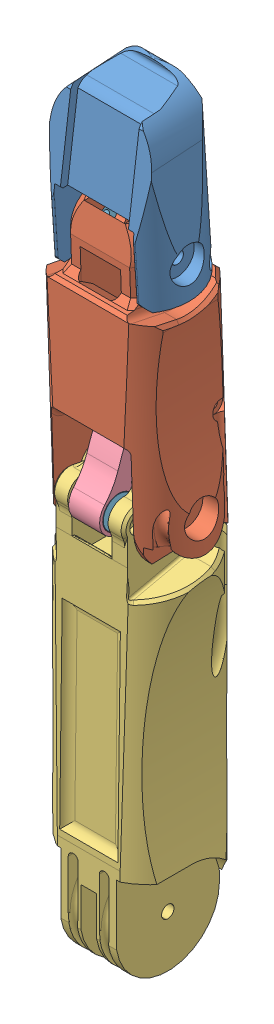
SolidWorks assembly assembly middle finger, configuration Default. Lengths in mm.
Overall size (26.12 124.19 19.82).
12 component instances, 5 part files, 24 mates.
Components (placement in the parent):
- middle link1-2: middle link1 [Default] at (0 -22.0125 -35.7101) x (1 0 0) z (0 -0.067342 0.99773) size (19.5 27.22 13.31)
- middle link2-2: middle link2 [Default] at (0 -57.5994 -36.9948) x (1 0 0) z (0 -0.036077 0.999349) size (23.01 45.61 15.34)
- middle link3-1: middle link3 [Default] at (0 -115.2194 -36.9948) size (26.12 70.93 19.35)
- middle linkage-1: middle linkage [Default] at (0 -39.6096 -36.4016) x (1 0 0) z (0 0.999451 0.033137) size (5 17.7 38.56)
- bearing 1.5-4-5-2-3: bearing 1.5-4-5-2 [Default] at (4.35 -57.5994 -36.9948) x (0 -0.484483 0.8748) z (0 0.8748 0.484483) size (5 2 5)
- bearing 1.5-4-5-2-4: bearing 1.5-4-5-2 [Default] at (0.5 -57.5994 -31.1248) x (0 -0.673592 0.739103) z (0 0.739103 0.673592) size (5 2 5)
- bearing 1.5-4-5-2-5: bearing 1.5-4-5-2 [Default] at (-4.35 -57.5994 -36.9948) x (0 0.90845 0.417993) z (0 -0.417993 0.90845) size (5 2 5)
- bearing 1.5-4-5-2-6: bearing 1.5-4-5-2 [Default] at (-0.5 -57.5994 -31.1248) x (0 0.90845 0.417993) z (0 -0.417993 0.90845) size (5 2 5)
- bearing 1.5-4-5-2-9: bearing 1.5-4-5-2 [Default] at (-0.5 -24.8761 -41.5454) x (0 0.90845 0.417993) z (0 -0.417993 0.90845) size (5 2 5)
- bearing 1.5-4-5-2-10: bearing 1.5-4-5-2 [Default] at (0.5 -24.8761 -41.5454) x (0 -0.673592 0.739103) z (0 0.739103 0.673592) size (5 2 5)
- bearing 1.5-4-5-2-11: bearing 1.5-4-5-2 [Default] at (-4.35 -22.0125 -35.7101) x (0 0.90845 0.417993) z (0 -0.417993 0.90845) size (5 2 5)
- bearing 1.5-4-5-2-12: bearing 1.5-4-5-2 [Default] at (4.35 -22.0125 -35.7101) x (0 -0.673592 0.739103) z (0 0.739103 0.673592) size (5 2 5)
Mates (geometry in assembly coordinates):
- Coincident1: coincident: plane of assembly through (0 0 0) normal (1 0 0); plane of middle link3-1 through (0 -115.2194 -36.9948) normal (1 0 0); plane of assembly
- Concentric1: concentric: cylinder of assembly; cylinder of assembly; cylinder of middle link2-2 through (7.4 -57.5994 -36.9948) axis (1 0 0) radius 2.75; cylinder of middle link3-1 through (-10.4 -57.5994 -36.9948) axis (1 0 0) radius 2.55
- Width1: width: plane of assembly; plane of assembly; plane of assembly; plane of assembly; plane of middle link2-2 through (-6.4 -45.3871 -42.6579) normal (1 0 0); plane of middle link2-2 through (6.4 -45.3871 -42.6579) normal (-1 0 0); plane of middle link3-1 through (-5.75 -62.8994 -36.9948) normal (-1 0 0); plane of middle link3-1 through (5.75 -62.8994 -36.9948) normal (1 0 0)
- Concentric3: concentric: cylinder of assembly; cylinder of assembly; cylinder of middle link1-2 through (7.3 -22.0125 -35.7101) axis (1 0 0) radius 2.75; cylinder of middle link2-2 through (-10.4 -22.0125 -35.7101) axis (1 0 0) radius 2.55
- Width2: width: plane of assembly; plane of assembly; plane of assembly; plane of assembly; plane of middle link1-2 through (-6.4 6.8469 -33.7623) normal (1 0 0); plane of middle link1-2 through (6.4 6.8469 -33.7623) normal (-1 0 0); plane of middle link2-2 through (5.75 -27.3091 -35.9013) normal (1 0 0); plane of middle link2-2 through (-5.75 -27.3091 -35.9013) normal (-1 0 0)
- Concentric4: concentric: cylinder of assembly; cylinder of assembly; cylinder of middle link3-1 through (-10.8126 -57.5994 -31.1248) axis (1 0 0) radius 0.65; cylinder of middle linkage-1 through (2.5 -57.5994 -31.1248) axis (-1 0 0) radius 2.075
- Width3: width: plane of middle link3-1 through (3.25 -120.2194 -43.0948) normal (-1 0 0); plane of middle link3-1 through (-3.25 -120.2194 -43.0948) normal (1 0 0); plane of middle linkage-1 through (2.5 -39.6096 -36.4016) normal (1 0 0); plane of middle linkage-1 through (-2.5 -39.6096 -36.4016) normal (-1 0 0)
- Concentric5: concentric: cylinder of middle link1-2 through (-10.0465 -24.8761 -41.5454) axis (1 0 0) radius 0.7; cylinder of middle linkage-1 through (2.5 -24.8761 -41.5454) axis (-1 0 0) radius 2.075
- Concentric9: concentric: cylinder of assembly; cylinder of assembly; cylinder of middle link3-1 through (-10.4 -57.5994 -36.9948) axis (1 0 0) radius 2.55; cylinder of bearing 1.5-4-5-2-3 through (6.35 -57.5994 -36.9948) axis (-1 0 0) radius 2
- Coincident4: coincident: plane of middle link3-1 through (5.75 -62.8994 -36.9948) normal (1 0 0); plane of bearing 1.5-4-5-2-3 through (5.75 -57.5994 -36.9948) normal (-1 0 0)
- Concentric10: concentric: cylinder of assembly; cylinder of assembly; cylinder of middle link3-1 through (-10.8126 -57.5994 -31.1248) axis (1 0 0) radius 0.65; cylinder of bearing 1.5-4-5-2-4 through (2.5 -57.5994 -31.1248) axis (-1 0 0) radius 2
- Coincident5: coincident: plane of middle linkage-1 through (1.9 -57.5994 -31.1248) normal (1 0 0); plane of bearing 1.5-4-5-2-4 through (1.9 -57.5994 -31.1248) normal (-1 0 0)
- Concentric11: concentric: cylinder of assembly; cylinder of assembly; cylinder of middle link3-1 through (-10.4 -57.5994 -36.9948) axis (1 0 0) radius 2.55; cylinder of bearing 1.5-4-5-2-5 through (-6.35 -57.5994 -36.9948) axis (1 0 0) radius 2
- Coincident6: coincident: plane of middle link3-1 through (-5.75 -62.8994 -36.9948) normal (-1 0 0); plane of bearing 1.5-4-5-2-5 through (-5.75 -57.5994 -36.9948) normal (1 0 0)
- Concentric12: concentric: cylinder of assembly; cylinder of assembly; cylinder of middle link3-1 through (-10.8126 -57.5994 -31.1248) axis (1 0 0) radius 0.65; cylinder of bearing 1.5-4-5-2-6 through (-2.5 -57.5994 -31.1248) axis (1 0 0) radius 2
- Coincident7: coincident: plane of middle linkage-1 through (-1.9 -57.5994 -31.1248) normal (-1 0 0); plane of bearing 1.5-4-5-2-6 through (-1.9 -57.5994 -31.1248) normal (1 0 0)
- Concentric15: concentric: cylinder of middle linkage-1 through (2.5 -24.8761 -41.5454) axis (-1 0 0) radius 2.075; cylinder of bearing 1.5-4-5-2-9 through (-2.5 -24.8761 -41.5454) axis (1 0 0) radius 2
- Coincident10: coincident: plane of middle linkage-1 through (-1.9 -24.8761 -41.5454) normal (-1 0 0); plane of bearing 1.5-4-5-2-9 through (-1.9 -24.8761 -41.5454) normal (1 0 0)
- Concentric16: concentric: cylinder of middle linkage-1 through (2.5 -24.8761 -41.5454) axis (-1 0 0) radius 2.075; cylinder of bearing 1.5-4-5-2-10 through (2.5 -24.8761 -41.5454) axis (-1 0 0) radius 2
- Coincident11: coincident: plane of middle linkage-1 through (1.9 -24.8761 -41.5454) normal (1 0 0); plane of bearing 1.5-4-5-2-10 through (1.9 -24.8761 -41.5454) normal (-1 0 0)
- Concentric17: concentric: cylinder of assembly; cylinder of assembly; cylinder of middle link2-2 through (-10.4 -22.0125 -35.7101) axis (1 0 0) radius 2.55; cylinder of bearing 1.5-4-5-2-12 through (6.35 -22.0125 -35.7101) axis (-1 0 0) radius 2
- Coincident12: coincident: plane of middle link2-2 through (5.75 -27.3091 -35.9013) normal (1 0 0); plane of bearing 1.5-4-5-2-12 through (5.75 -22.0125 -35.7101) normal (-1 0 0)
- Coincident13: coincident: plane of assembly; plane of assembly; plane of middle link2-2 through (-5.75 -27.3091 -35.9013) normal (-1 0 0); plane of bearing 1.5-4-5-2-11 through (-5.75 -22.0125 -35.7101) normal (1 0 0)
- Concentric18: concentric: cylinder of middle link2-2 through (-10.4 -22.0125 -35.7101) axis (1 0 0) radius 2.55; cylinder of bearing 1.5-4-5-2-11 through (-6.35 -22.0125 -35.7101) axis (1 0 0) radius 2
